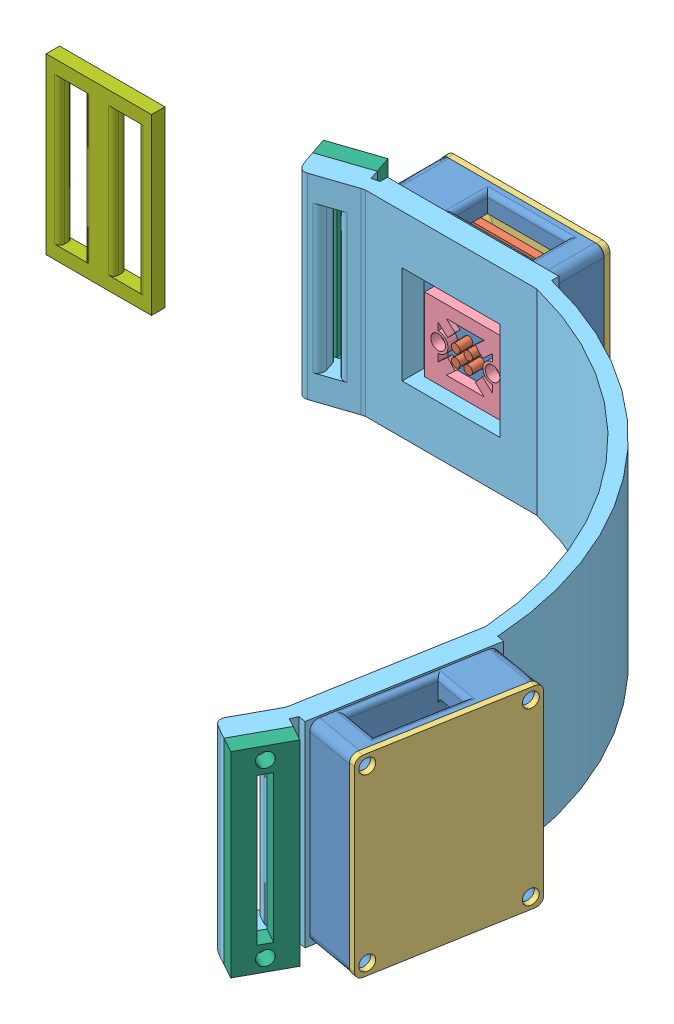
SolidWorks assembly ActiveElectrodeHeadset, configuration Default. Lengths in mm.
Overall size (176.75 42.03 147.5).
12 component instances, 7 part files, 29 mates.
Components (placement in the parent):
- FacePlate-1: FacePlate [Default] at (-27.7858 -15.6159 12.4304) size (33.31 39.28 10)
- PCB-1: PCB [Default] at (-27.7858 -15.6159 7.9304) size (24.13 30.1 9.98)
- PCB_Pad-2: PCB_Pad [Default] at (-27.7858 -15.6159 3.6804) size (33.31 39.28 3.25)
- SpongeAttachment-1: SpongeAttachment [Default] at (-27.7858 10.5741 15.6804) x (1 0 0) z (0 0 -1) size (16.6 15 2)
- Bracket-1: Bracket [Default] at (-15.7218 -20.5659 88.1102) x (0.642788 0 0.766044) z (0 1 0) size (146.86 53.09 40)
- ElasticClamp-1: ElasticClamp [Default] at (-40.2535 19.4341 15.3131) x (0 1 0) z (0.319343 0 0.947639) size (40 10.4 3.5)
- ElasticClamp-2: ElasticClamp [Default] at (54.7817 19.4341 126.587) x (0 1 0) z (0.877789 0 0.479048) size (40 10.4 3.5)
- PCB_Pad-3: PCB_Pad [Default] at (69.5205 -15.6159 90.8886) x (-0.173648 0 0.984808) z (-0.984808 0 -0.173648) size (33.31 39.28 3.25)
- FacePlate-2: FacePlate [Default] at (60.9035 -15.6159 89.3692) x (-0.173648 0 0.984808) z (-0.984808 0 -0.173648) size (33.31 39.28 10)
- PCB-2: PCB [Default] at (65.3351 -15.6159 90.1506) x (-0.173648 0 0.984808) z (-0.984808 0 -0.173648) size (24.13 30.1 9.98)
- SpongeAttachment-2: SpongeAttachment [Default] at (53.3762 -15.6159 113.3424) x (0.173648 0 -0.984808) z (0.984808 0 0.173648) size (16.6 15 2)
- ElasticBracket-1: ElasticBracket [Default] at (-87.821 -11.2817 25.9715) size (21.5 35.5 2.75)
Mates (geometry in assembly coordinates):
- Coincident8: coincident aligned: circle of FacePlate-1; circle of PCB_Pad-2
- Coincident9: coincident aligned: circle of FacePlate-1; circle of PCB_Pad-2
- Coincident16: coincident anti-aligned: circle of FacePlate-1; circle of SpongeAttachment-1
- Coincident17: coincident anti-aligned: circle of FacePlate-1; circle of SpongeAttachment-1
- Concentric1: concentric aligned: circle of FacePlate-1; circle of PCB-1
- Concentric2: concentric aligned: circle of FacePlate-1; circle of PCB-1
- Coincident20: coincident anti-aligned: plane of FacePlate-1 through (-27.7858 -15.6159 7.9304) normal (0 0 -1); plane of PCB-1 through (-27.7858 -15.6159 7.9304) normal (0 0 1)
- Coincident28: coincident aligned: circle of FacePlate-1; circle of Bracket-1
- Coincident29: coincident anti-aligned: circle of FacePlate-1; circle of Bracket-1
- Concentric3: concentric aligned: cylinder of Bracket-1 through (-40.2535 -18.0659 15.3131) axis (0.319343 0 0.947639) radius 1.5; cylinder of ElasticClamp-1 through (-41.3712 -18.0659 11.9964) axis (0.319343 0 0.947639) radius 1.5
- Coincident30: coincident aligned: plane of Bracket-1 through (-45.1832 -20.5659 16.9744) normal (-0.947639 0 0.319343); plane of ElasticClamp-1 through (-46.3009 -20.5659 13.6577) normal (-0.947639 0 0.319343)
- Coincident31: coincident anti-aligned: plane of Bracket-1 through (-40.2535 -20.5659 15.3131) normal (-0.319343 0 -0.947639); plane of ElasticClamp-1 through (-40.2535 19.4341 15.3131) normal (0.319343 0 0.947639)
- Concentric4: concentric anti-aligned: cylinder of Bracket-1 through (51.7094 16.9341 124.9103) axis (-0.877789 0 -0.479048) radius 1.5; cylinder of ElasticClamp-2 through (51.7094 16.9341 124.9103) axis (0.877789 0 0.479048) radius 1.5
- Coincident32: coincident aligned: plane of Bracket-1 through (49.2174 19.4341 129.4767) normal (-0.479048 0 0.877789); plane of ElasticClamp-2 through (49.2174 -20.5659 129.4767) normal (-0.479048 0 0.877789)
- Coincident33: coincident anti-aligned: plane of Bracket-1 through (51.7094 -20.5659 124.9103) normal (0.877789 0 0.479048); plane of ElasticClamp-2 through (51.7094 19.4341 124.9103) normal (-0.877789 0 -0.479048)
- Concentric5: concentric aligned: cylinder of FacePlate-2 through (65.3232 -12.6949 111.8136) axis (-0.984808 0 -0.173648) radius 1.125; cylinder of PCB-2 through (63.2058 -12.6949 111.4403) axis (-0.984808 0 -0.173648) radius 1.5
- Concentric6: concentric aligned: cylinder of FacePlate-2 through (68.4989 -12.6949 93.8034) axis (-0.984808 0 -0.173648) radius 1.125; cylinder of PCB-2 through (66.3815 -12.6949 93.4301) axis (-0.984808 0 -0.173648) radius 1.5
- Concentric7: concentric aligned: cylinder of FacePlate-2 through (68.4989 11.4351 93.8034) axis (-0.984808 0 -0.173648) radius 1.125; cylinder of PCB-2 through (66.3815 11.4351 93.4301) axis (-0.984808 0 -0.173648) radius 1.5
- Concentric8: concentric anti-aligned: cylinder of PCB_Pad-3 through (71.1581 16.8241 88.8002) axis (-0.984808 0 -0.173648) radius 1.5; cylinder of FacePlate-2 through (60.079 16.8241 86.8467) axis (0.984808 0 0.173648) radius 1.5
- Concentric9: concentric anti-aligned: cylinder of PCB_Pad-3 through (71.1581 -17.9569 88.8002) axis (-0.984808 0 -0.173648) radius 1.5; cylinder of FacePlate-2 through (60.079 -17.9569 86.8467) axis (0.984808 0 0.173648) radius 1.5
- Concentric10: concentric anti-aligned: cylinder of PCB_Pad-3 through (66.1549 16.8241 117.1745) axis (-0.984808 0 -0.173648) radius 1.5; cylinder of FacePlate-2 through (55.0758 16.8241 115.2209) axis (0.984808 0 0.173648) radius 1.5
- Coincident35: coincident anti-aligned: plane of PCB_Pad-3 through (69.5205 -15.6159 90.8886) normal (-0.984808 0 -0.173648); plane of FacePlate-2 through (69.5205 -15.6159 90.8886) normal (0.984808 0 0.173648)
- Coincident36: coincident anti-aligned: plane of FacePlate-2 through (65.3351 -15.6159 90.1506) normal (0.984808 0 0.173648); plane of PCB-2 through (65.3351 -15.6159 90.1506) normal (-0.984808 0 -0.173648)
- Concentric11: concentric aligned: cylinder of Bracket-1 through (51.3828 16.8241 114.5698) axis (0.984808 0 0.173648) radius 1.5; cylinder of FacePlate-2 through (55.0758 16.8241 115.2209) axis (0.984808 0 0.173648) radius 1.5
- Concentric12: concentric aligned: cylinder of Bracket-1 through (51.3828 -17.9559 114.5698) axis (0.984808 0 0.173648) radius 1.5; cylinder of FacePlate-2 through (55.0758 -17.9569 115.2209) axis (0.984808 0 0.173648) radius 1.5
- Coincident37: coincident anti-aligned: plane of Bracket-1 through (57.5772 -20.5659 101.0348) normal (0.984808 0 0.173648); plane of FacePlate-2 through (59.6725 -15.6159 89.1521) normal (-0.984808 0 -0.173648)
- Coincident38: coincident anti-aligned: plane of FacePlate-2 through (59.6725 -15.6159 89.1521) normal (-0.984808 0 -0.173648); plane of SpongeAttachment-2 through (55.3458 -15.6159 113.6897) normal (0.984808 0 0.173648)
- Concentric15: concentric anti-aligned: cylinder of FacePlate-2 through (58.4729 -2.5209 95.9552) axis (0.984808 0 0.173648) radius 1.5; cylinder of SpongeAttachment-2 through (58.4729 -2.5209 95.9552) axis (-0.984808 0 -0.173648) radius 1.5
- Concentric16: concentric anti-aligned: cylinder of FacePlate-2 through (56.5454 -2.5209 106.8866) axis (0.984808 0 0.173648) radius 1.5; cylinder of SpongeAttachment-2 through (56.5454 -2.5209 106.8866) axis (-0.984808 0 -0.173648) radius 1.5
